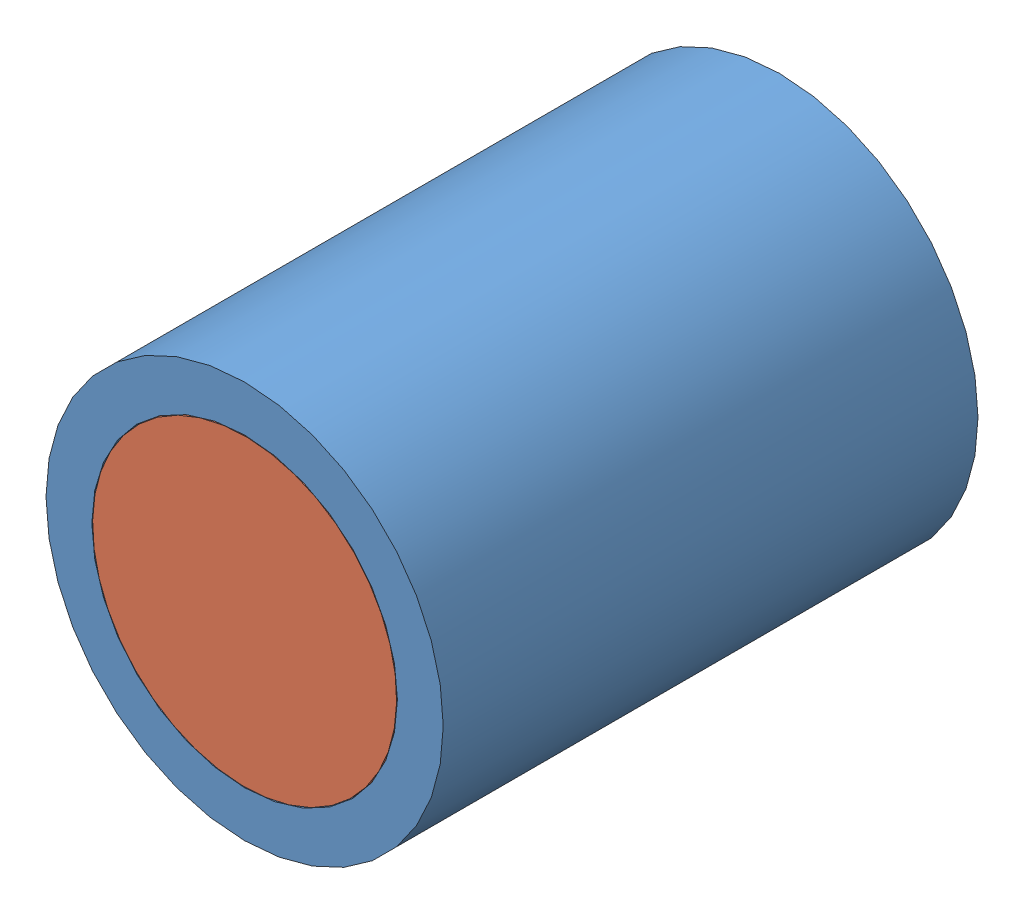
SolidWorks assembly Assem3, configuration Default. Lengths in mm.
Overall size (26 26 35).
2 component instances, 2 part files, 2 mates.
Components (placement in the parent):
- cannon2-1: cannon2 [Default] at (-0.4012 28.5254 14.999) size (26 26 35)
- cannon3-1: cannon3 [Default] at (-0.4012 28.5254 44.999) x (0.999841 -0.017852 0) z (0 0 1) size (19.9 19.9 15)
Mates (geometry in assembly coordinates):
- Concentric1: concentric aligned: cylinder of cannon2-1 through (-0.4012 28.5254 49.999) axis (0 0 -1) radius 10; cylinder of cannon3-1 through (-0.4012 28.5254 49.999) axis (0 0 -1) radius 9.95
- Coincident2: coincident aligned: plane of cannon2-1 through (-0.4012 28.5254 49.999) normal (0 0 1); circle of cannon3-1
